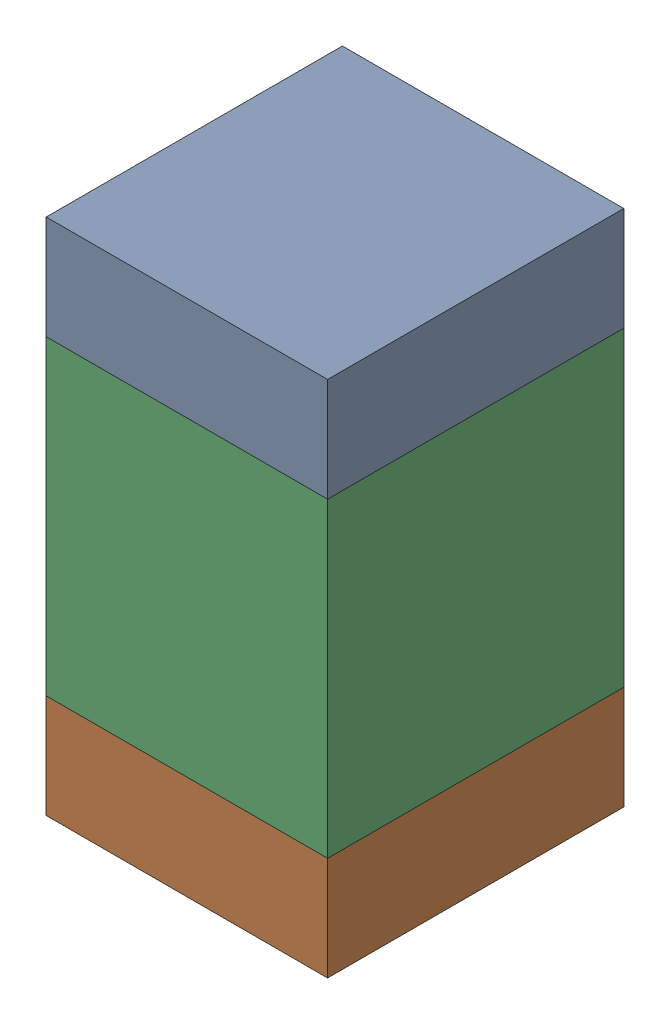
SolidWorks assembly C10-2, configuration Default. Lengths in mm.
Overall size (0.95 1.75 1).
6 component instances, 2 part files, 0 mates.
Components (placement in the parent):
- 959208664-2-1: 959208664-2 [Default] at (109.7632 77.5843 0) size (0.95 0.35 1)
  - Extruded-76-1: Extruded-76 [Default] at origin size (0.95 0.35 1)
- 959208664-2-2: 959208664-2 [Default] at (109.7632 76.1843 0) size (0.95 0.35 1)
  - Extruded-76-1: Extruded-76 [Default] at origin size (0.95 0.35 1)
- 959208528-2-1: 959208528-2 [Default] at (109.7632 76.8843 0) size (0.95 1.05 1)
  - Extruded-77-1: Extruded-77 [Default] at origin size (0.95 1.05 1)
